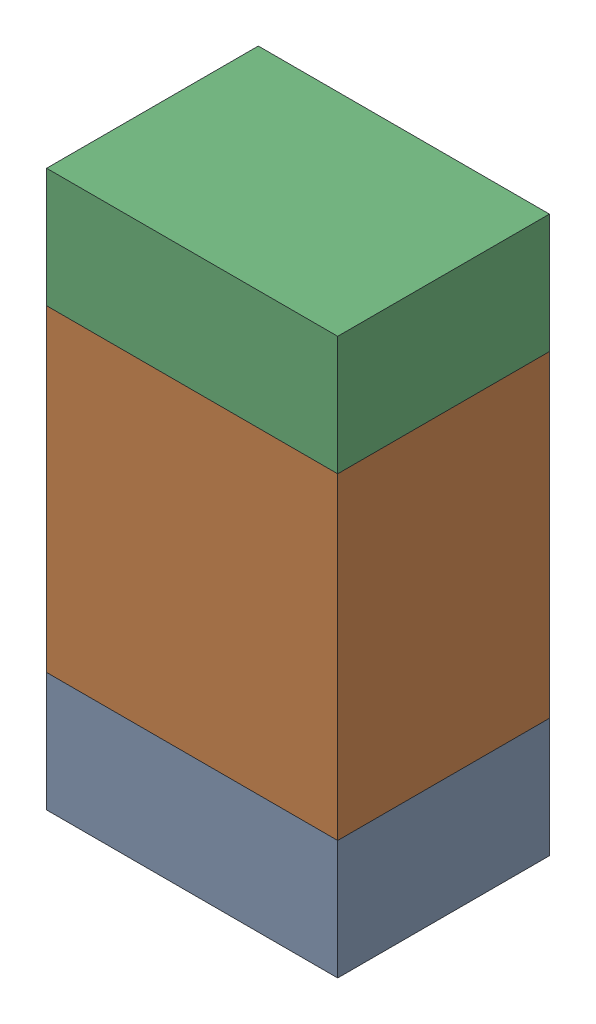
SolidWorks assembly R605_1PCB, configuration Default. Lengths in mm.
Overall size (0.55 1.05 0.4).
6 component instances, 2 part files, 0 mates.
Components (placement in the parent):
- 846483288-1: 846483288 [Default] at (100.0001 108.4876 -2.0638) size (0.55 0.22 0.4)
  - Extruded_12-1: Extruded_12 [Default] at origin size (0.55 0.22 0.4)
- 846483424-1: 846483424 [Default] at (100.0001 108.9001 -2.0638) size (0.55 0.6 0.4)
  - Extruded_13-1: Extruded_13 [Default] at origin size (0.55 0.6 0.4)
- 846483288-2: 846483288 [Default] at (100.0001 109.3126 -2.0638) size (0.55 0.22 0.4)
  - Extruded_12-1: Extruded_12 [Default] at origin size (0.55 0.22 0.4)
